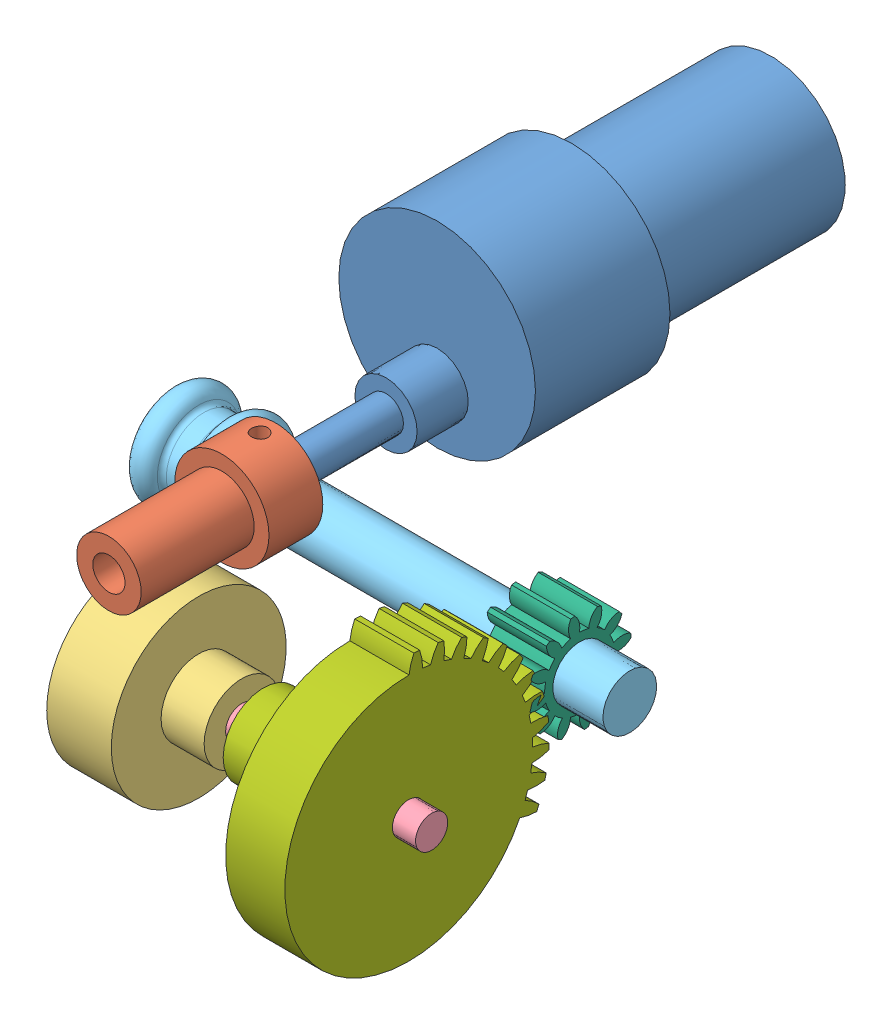
SolidWorks assembly mech assss, configuration Default. Lengths in mm.
Overall size (85 87.84 147.83).
8 component instances, 7 part files, 10 mates.
Components (placement in the parent):
- motor 2-1: motor 2 [Default] at (-20.0328 -8.9413 64.9846) size (36.56 36.56 102.5)
- worm gear part 1-1: worm gear part 1 [Default] at (-20.0328 -16.9313 156.9846) size (17.5 17.5 31)
- worm gear part 2-1: worm gear part 2 [Default] at (-26.0328 -39.1813 177.2924) x (0 0 -1) z (1 0 0) size (32.5 32.5 20)
- shaft between 2pi3 and wom-1: shaft between 2pi3 and wom [Default] at (-30.7361 -39.1813 177.2924) x (0 0.802001 0.597323) z (1 0 0) size (6 6 60)
- pulley-2: pulley [Default] at (-44.3299 -25.0187 147.6459) x (-1 0 0) z (0 0.31071 -0.950505) size (85 19 19)
- gears 1-1: gears 1 [Default] at (13.95 -59.0816 166.6961) x (0 0.790654 -0.612263) z (1 0 0) size (61.36 56.97 35)
  - spur gear_am-3: spur gear_am [Metric - Spur gear 1.375M 12T 14.5PA 11FW ---S12B8H27L6N] at (34.6667 0 11) x (0 0 -1) z (-0.999975 -0.007046 0) size (27 18.78 18.78)
  - big spur-1: big spur [Default] at (12.6363 23.1331 -6.996) x (0 0 1) z (0.98635 0.164665 0) size (27 49.1 49.1)
Mates (geometry in assembly coordinates):
- Concentric2: concentric: cylinder of motor 2-1 through (-20.0328 -16.9313 167.4846) axis (0 0 -1) radius 3.25; cylinder of worm gear part 1-1 through (-20.0328 -16.9313 187.9846) axis (0 0 -1) radius 3
- Concentric3: concentric: cylinder of motor 2-1 through (-20.0328 -28.9413 159.9846) axis (0 1 0) radius 1.5; cylinder of worm gear part 1-1 through (-20.0328 -25.6813 159.9846) axis (0 1 0) radius 1.5
- Tangent2: tangent: cylinder of worm gear part 1-1 through (-20.0328 -16.9313 166.9846) axis (0 0 1) radius 6; cylinder of worm gear part 2-1 through (-6.0328 -39.1813 177.2924) axis (-1 0 0) radius 16.25
- Parallel3: parallel: plane of worm gear part 1-1 through (-20.0328 -16.9313 156.9846) normal (0 0 1); plane of worm gear part 2-1 through (-26.0328 -39.1813 177.2924) normal (0 0 -1)
- Tangent3: tangent: cylinder of worm gear part 1-1 through (-20.0328 -16.9313 166.9846) axis (0 0 1) radius 6; plane of worm gear part 2-1 through (-26.0328 -39.1813 177.2924) normal (-1 0 0)
- Concentric4: concentric: cylinder of worm gear part 2-1 through (-26.0328 -39.1813 177.2924) axis (1 0 0) radius 3; cylinder of shaft between 2pi3 and wom-1 through (29.2639 -39.1813 177.2924) axis (-1 0 0) radius 3
- Distance2: distance = 5 mm: plane of pulley-2 through (-35.7361 -25.0187 147.6459) normal (1 0 0); plane of shaft between 2pi3 and wom-1 through (-30.7361 -39.1813 177.2924) normal (-1 0 0)
- Concentric9: concentric: cylinder of shaft between 2pi3 and wom-1 through (29.2639 -39.1813 177.2924) axis (-1 0 0) radius 3; cylinder of gears 1-1/big spur-1 through (-2.05 -39.1813 177.2924) axis (1 0 0) radius 2.9909
- Concentric10: concentric: cylinder of pulley-2 through (34.2639 -31.6722 145.471) axis (-1 0 0) radius 5; cylinder of gears 1-1/spur gear_am-3 through (-2.05 -31.6722 145.471) axis (1 0 0) radius 3
- Parallel6: parallel: cylinder of shaft between 2pi3 and wom-1 through (29.2639 -39.1813 177.2924) axis (-1 0 0) radius 3; cylinder of pulley-2 through (34.2639 -31.6722 145.471) axis (-1 0 0) radius 5
